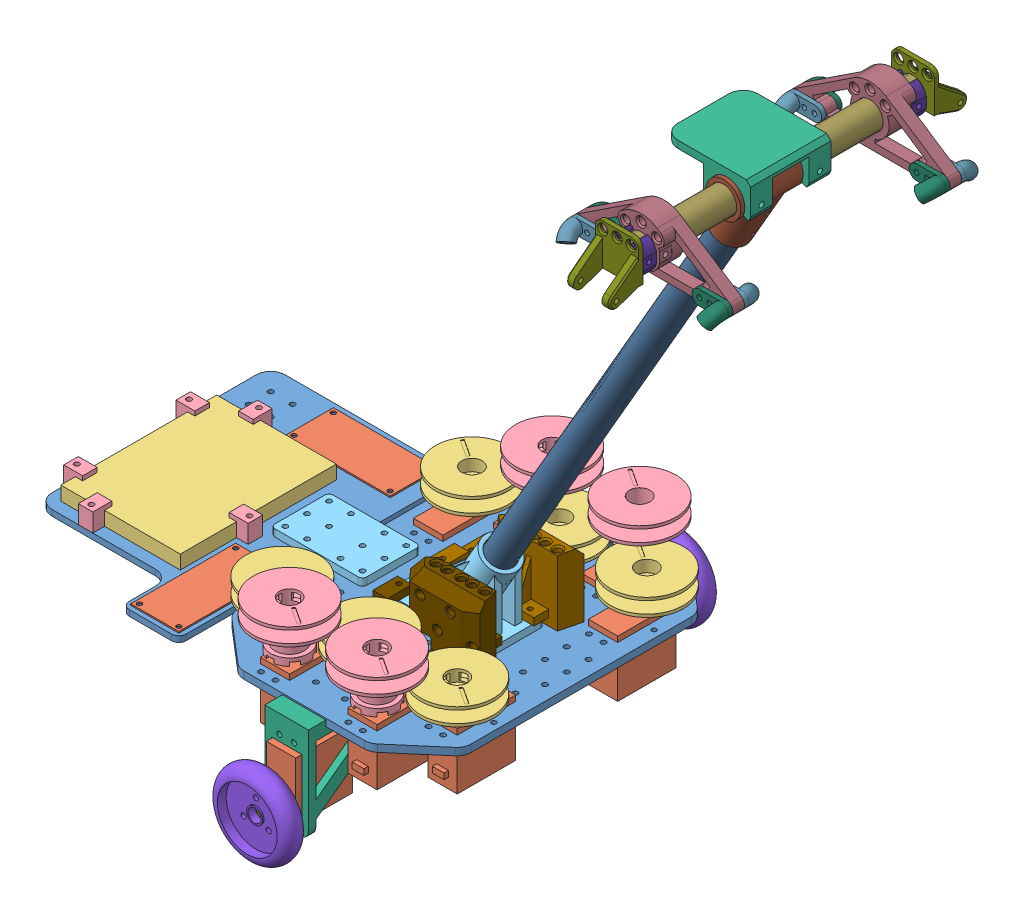
SolidWorks assembly link_root, configuration ﾃﾞﾌｫﾙﾄ. Lengths in mm.
Overall size (475.55 460.7 298.2).
76 component instances, 24 part files, 39 mates.
Components (placement in the parent):
- base_motor-1: base_motor [ﾃﾞﾌｫﾙﾄ] at origin size (192.73 130.6 298.2)
  - base-1: base [ﾃﾞﾌｫﾙﾄ] at origin size (160.1 5 220.2)
  - motor-1: motor [ﾃﾞﾌｫﾙﾄ] at (0 -30 -30.05) x (0 0 1) z (-1 0 0) size (73.36 59.5 70.97)
    - FB5311M-1: FB5311M [ﾃﾞﾌｫﾙﾄ] at origin size (54 44.25 20.1)
    - servo_horn_short-1: servo_horn_short [ﾃﾞﾌｫﾙﾄ] at (-10 42.5 0) x (-0.837169 0 -0.546944) z (0 1 0) size (50 57.04 17)
  - motor-2: motor [ﾃﾞﾌｫﾙﾄ] at (-60 -30 -30.05) x (0 0 1) z (-1 0 0) size (73.36 59.5 70.97)
    - FB5311M-1: FB5311M [ﾃﾞﾌｫﾙﾄ] at origin size (54 44.25 20.1)
    - servo_horn_short-1: servo_horn_short [ﾃﾞﾌｫﾙﾄ] at (-10 42.5 0) x (-0.837169 0 -0.546944) z (0 1 0) size (50 57.04 17)
  - motor-3: motor [ﾃﾞﾌｫﾙﾄ] at (60 -30 -30.05) x (0 0 1) z (-1 0 0) size (73.36 59.5 70.97)
    - FB5311M-1: FB5311M [ﾃﾞﾌｫﾙﾄ] at origin size (54 44.25 20.1)
    - servo_horn_short-1: servo_horn_short [ﾃﾞﾌｫﾙﾄ] at (-10 42.5 0) x (-0.837169 0 -0.546944) z (0 1 0) size (50 57.04 17)
  - motor_long-6: motor_long [ﾃﾞﾌｫﾙﾄ] at (-30 -30 -55.05) x (0 0 1) z (-1 0 0) size (75.45 74.5 73.44) (flexible)
    - FB5311M-1: FB5311M [ﾃﾞﾌｫﾙﾄ] at origin size (54 44.25 20.1)
    - servo_horn_long-1: servo_horn_long [ﾃﾞﾌｫﾙﾄ] at (-10 42.5 0) x (0.789041 0 0.61434) z (0 1 0) size (50 57.04 32)
  - motor_long-5: motor_long [ﾃﾞﾌｫﾙﾄ] at (30 -30 -55.05) x (0 0 1) z (-1 0 0) size (75.45 74.5 73.44)
    - FB5311M-1: FB5311M [ﾃﾞﾌｫﾙﾄ] at origin size (54 44.25 20.1)
    - servo_horn_long-1: servo_horn_long [ﾃﾞﾌｫﾙﾄ] at (-10 42.5 0) x (-0.837169 0 -0.546944) z (0 1 0) size (50 57.04 32)
  - connector_45-1: connector_45 [ﾃﾞﾌｫﾙﾄ] at (0 10 25) x (0 0 1) z (0 1 0) size (40 70.39 54.3)
  - motor-4: motor [ﾃﾞﾌｫﾙﾄ] at (-60 -30 80.05) x (0 0 -1) z (1 0 0) size (73.36 59.5 70.97)
    - FB5311M-1: FB5311M [ﾃﾞﾌｫﾙﾄ] at origin size (54 44.25 20.1)
    - servo_horn_short-1: servo_horn_short [ﾃﾞﾌｫﾙﾄ] at (-10 42.5 0) x (-0.837169 0 -0.546944) z (0 1 0) size (50 57.04 17)
  - motor-5: motor [ﾃﾞﾌｫﾙﾄ] at (0 -30 80.05) x (0 0 -1) z (1 0 0) size (73.36 59.5 70.97)
    - FB5311M-1: FB5311M [ﾃﾞﾌｫﾙﾄ] at origin size (54 44.25 20.1)
    - servo_horn_short-1: servo_horn_short [ﾃﾞﾌｫﾙﾄ] at (-10 42.5 0) x (-0.837169 0 -0.546944) z (0 1 0) size (50 57.04 17)
  - motor-6: motor [ﾃﾞﾌｫﾙﾄ] at (60 -30 80.05) x (0 0 -1) z (1 0 0) size (73.36 59.5 70.97)
    - FB5311M-1: FB5311M [ﾃﾞﾌｫﾙﾄ] at origin size (54 44.25 20.1)
    - servo_horn_short-1: servo_horn_short [ﾃﾞﾌｫﾙﾄ] at (-10 42.5 0) x (-0.837169 0 -0.546944) z (0 1 0) size (50 57.04 17)
  - motor_long-7: motor_long [ﾃﾞﾌｫﾙﾄ] at (-30 -30 105.05) x (0 0 -1) z (1 0 0) size (75.45 74.5 73.44)
    - FB5311M-1: FB5311M [ﾃﾞﾌｫﾙﾄ] at origin size (54 44.25 20.1)
    - servo_horn_long-1: servo_horn_long [ﾃﾞﾌｫﾙﾄ] at (-10 42.5 0) x (-0.837169 0 -0.546944) z (0 1 0) size (50 57.04 32)
  - motor_long-8: motor_long [ﾃﾞﾌｫﾙﾄ] at (30 -30 105.05) x (0 0 -1) z (1 0 0) size (75.45 74.5 73.44)
    - FB5311M-1: FB5311M [ﾃﾞﾌｫﾙﾄ] at origin size (54 44.25 20.1)
    - servo_horn_long-1: servo_horn_long [ﾃﾞﾌｫﾙﾄ] at (-10 42.5 0) x (-0.837169 0 -0.546944) z (0 1 0) size (50 57.04 32)
  - wheel_motor-1: wheel_motor [ﾃﾞﾌｫﾙﾄ] at (15 -61.5 -92.1) x (-1 0 0) z (0 0 -1) size (56 75.3 72)
    - wheel_motor_mount-1: wheel_motor_mount [ﾃﾞﾌｫﾙﾄ] at origin size (30 65.5 45)
    - FB5311M-1: FB5311M [ﾃﾞﾌｫﾙﾄ] at (15 28.2 -30) x (0 1 0) z (1 0 0) size (54 44.25 20.1)
    - wheel_horn-1: wheel_horn [ﾃﾞﾌｫﾙﾄ] at (15 18.2 15.5) size (26 26 10.5)
    - tire-1: tire [ﾃﾞﾌｫﾙﾄ] at (15 18.2 24.5) x (0 0 -1) z (1 0 0) size (15 56 56)
  - wheel_motor-2: wheel_motor [ﾃﾞﾌｫﾙﾄ] at (-15 -61.5 142.1) size (56 75.3 72)
    - wheel_motor_mount-1: wheel_motor_mount [ﾃﾞﾌｫﾙﾄ] at origin size (30 65.5 45)
    - FB5311M-1: FB5311M [ﾃﾞﾌｫﾙﾄ] at (15 28.2 -30) x (0 1 0) z (1 0 0) size (54 44.25 20.1)
    - wheel_horn-1: wheel_horn [ﾃﾞﾌｫﾙﾄ] at (15 18.2 15.5) size (26 26 10.5)
    - tire-1: tire [ﾃﾞﾌｫﾙﾄ] at (15 18.2 24.5) x (0 0 -1) z (1 0 0) size (15 56 56)
- root_connector_loft-1: root_connector_loft [ﾃﾞﾌｫﾙﾄ] at (0 5 -10) x (0 0 -1) z (1 0 0) size (39 45 81.16)
- pipe_body-1: pipe_body [body] at (202.5 360.7403 25) x (-0.866025 0.5 0) z (-0.5 -0.866025 0) size (18 18 400)
- connector_T-1: connector_T [ﾃﾞﾌｫﾙﾄ] at (207.5 369.4005 25) x (-0.5 -0.866025 0) z (-0.866025 0.5 0) size (62 60 24)
- pipe_shoulder-1: pipe_shoulder [ﾃﾞﾌｫﾙﾄ] at (207.5 369.4005 -75) size (18 18 200)
- assem_shoulder-3: assem_shoulder [left] at (207.5 369.4005 -45.5) x (-1 0 0) z (0 0 -1) size (110 42.64 39.98)
  - wire_root_curve-1: wire_root_curve [ﾃﾞﾌｫﾙﾄ] at origin size (110 40 16)
  - wire_root_curve_support-1: wire_root_curve_support [ﾃﾞﾌｫﾙﾄ] at (-50 -15 11) size (25 12.64 15.99)
  - wire_root_curve_support_mirror-1: wire_root_curve_support_mirror [ﾃﾞﾌｫﾙﾄ] at (50 -15 5) x (-1 0 0) z (0 0 -1) size (25 12.64 15.99)
  - wire_root_curve_support-2: wire_root_curve_support [45] at (50 -15 -3) x (-1 0 0) z (0 0 -1) size (25 12.5 15.99)
  - wire_root_curve_support_mirror-2: wire_root_curve_support_mirror [76] at (-50 -15 3) size (25 12.37 15.99)
- assem_shoulder-2: assem_shoulder [ﾃﾞﾌｫﾙﾄ] at (207.5 369.4005 95.5) size (110 42.64 39.98)
  - wire_root_curve-1: wire_root_curve [ﾃﾞﾌｫﾙﾄ] at origin size (110 40 16)
  - wire_root_curve_support-1: wire_root_curve_support [ﾃﾞﾌｫﾙﾄ] at (-50 -15 11) size (25 12.64 15.99)
  - wire_root_curve_support_mirror-1: wire_root_curve_support_mirror [ﾃﾞﾌｫﾙﾄ] at (50 -15 5) x (-1 0 0) z (0 0 -1) size (25 12.64 15.99)
  - wire_root_curve_support-2: wire_root_curve_support [76] at (50 -15 -3) x (-1 0 0) z (0 0 -1) size (25 12.37 15.99)
  - wire_root_curve_support_mirror-2: wire_root_curve_support_mirror [45] at (-50 -15 3) size (25 12.5 15.99)
- shoulder3-1: shoulder3 [ﾃﾞﾌｫﾙﾄ] at (207.5 369.4005 -60) x (1 0 0) z (0 0 -1) size (29.5 33 38)
- shoulder3-2: shoulder3 [ﾃﾞﾌｫﾙﾄ] at (207.5 369.4005 110) x (-1 0 0) z (0 0 1) size (29.5 33 38)
- shoulder_patch-1: shoulder_patch [ﾃﾞﾌｫﾙﾄ] at (207.5 369.4005 112.5) size (23.48 22.98 10)
- shoulder_patch-2: shoulder_patch [ﾃﾞﾌｫﾙﾄ] at (207.5 369.4005 -72.5) size (23.48 22.98 10)
- root_connector_loft_mirror-1: root_connector_loft_mirror [ﾃﾞﾌｫﾙﾄ] at (0 5 60) x (0 0 -1) z (1 0 0) size (39 45 81.16)
- circuit-1: circuit [ﾃﾞﾌｫﾙﾄ] at (-148.05 1 25) x (0 0 1) z (-1 0 0) size (193 16.5 130)
  - circuit_board-1: circuit_board [ﾃﾞﾌｫﾙﾄ] at origin size (193 4 130)
  - PCA9685-1: PCA9685 [ﾃﾞﾌｫﾙﾄ] at (-59.5 4 -18) x (0 0 1) z (-1 0 0) size (72 1 33)
  - breadboard-1: breadboard [ﾃﾞﾌｫﾙﾄ] at (18.5 4 16) size (107 9.5 82)
  - PCA9685-2: PCA9685 [ﾃﾞﾌｫﾙﾄ] at (74 4 -45.5) x (-1 0 0) z (0 0 -1) size (72 1 33)
  - breadboard_support-1: breadboard_support [ﾃﾞﾌｫﾙﾄ] at (72 4 27) size (13 12.5 10)
  - breadboard_support-2: breadboard_support [ﾃﾞﾌｫﾙﾄ] at (62 4 57) x (0 0 1) z (-1 0 0) size (13 12.5 10)
  - breadboard_support-3: breadboard_support [ﾃﾞﾌｫﾙﾄ] at (-15 4 57) x (0 0 1) z (-1 0 0) size (13 12.5 10)
  - breadboard_support-4: breadboard_support [ﾃﾞﾌｫﾙﾄ] at (-35 4 37) x (-1 0 0) z (0 0 -1) size (13 12.5 10)
  - breadboard_support-5: breadboard_support [ﾃﾞﾌｫﾙﾄ] at (23.5 4 -25) x (0 0 -1) z (1 0 0) size (13 12.5 10)
- board_connect-1: board_connect [ﾃﾞﾌｫﾙﾄ] at (-81.55 5 25) x (0 0 -1) z (1 0 0) size (40 5 63)
- camera_mount-1: camera_mount [ﾃﾞﾌｫﾙﾄ] at (207.5 369.4005 25) x (0 0 1) z (-1 0 0) size (55 23.79 60)
Mates (geometry in assembly coordinates):
- 同心円2: concentric anti-aligned: cylinder of base_motor-1/base-1 through (-20 0 -20) axis (0 1 0) radius 1.75; cylinder of root_connector_loft-1 through (-20 10 -20) axis (0 -1 0) radius 1.75
- 同心円3: concentric anti-aligned: cylinder of base_motor-1/base-1 through (-30 0 -10) axis (0 1 0) radius 1.75; cylinder of root_connector_loft-1 through (-30 10 -10) axis (0 -1 0) radius 1.75
- 一致1: coincident anti-aligned: plane of base_motor-1/base-1 through (0 5 50) normal (0 1 0); plane of root_connector_loft-1 through (0 5 -10) normal (0 -1 0)
- 同心円6: concentric aligned: cylinder of base_motor-1/connector_45-1 through (-10.9151 -8.9054 25) axis (0.5 0.866025 0) radius 9.4; cylinder of pipe_body-1 through (2.5 14.3301 25) axis (0.5 0.866025 0) radius 9
- 同心円7: concentric anti-aligned: cylinder of base_motor-1/connector_45-1 through (-27.5993 72.1225 25) axis (0.866025 -0.5 0) radius 1.75; cylinder of pipe_body-1 through (27.7942 40.141 25) axis (-0.866025 0.5 0) radius 1.75
- 同心円8: concentric anti-aligned: cylinder of pipe_body-1 through (2.5 14.3301 25) axis (0.5 0.866025 0) radius 9; cylinder of connector_T-1 through (213.501 379.7946 25) axis (-0.5 -0.866025 0) radius 9.25
- 同心円9: concentric aligned: cylinder of pipe_body-1 through (205.2942 347.58 25) axis (-0.866025 0.5 0) radius 1.75; cylinder of connector_T-1 through (207.8923 346.08 25) axis (-0.866025 0.5 0) radius 1.75
- 同心円10: concentric aligned: cylinder of connector_T-1 through (207.5 369.4005 55) axis (0 0 -1) radius 9.25; cylinder of pipe_shoulder-1 through (207.5 369.4005 125) axis (0 0 -1) radius 9
- 同心円11: concentric anti-aligned: cylinder of connector_T-1 through (223.8923 369.4005 45) axis (-1 0 0) radius 1.75; cylinder of pipe_shoulder-1 through (198.5 369.4005 45) axis (1 0 0) radius 1.75
- 同心円12: concentric anti-aligned: cylinder of pipe_shoulder-1 through (207.5 369.4005 125) axis (0 0 -1) radius 9; cylinder of assem_shoulder-3/wire_root_curve-1 through (207.5 369.4005 -53.5) axis (0 0 1) radius 9.25
- 同心円13: concentric anti-aligned: cylinder of pipe_shoulder-1 through (198.5 369.4005 -57.5) axis (1 0 0) radius 1.75; cylinder of assem_shoulder-3/wire_root_curve-1 through (262.5 369.4005 -57.5) axis (-1 0 0) radius 1.75
- 同心円14: concentric aligned: cylinder of pipe_shoulder-1 through (207.5 369.4005 125) axis (0 0 -1) radius 9; cylinder of assem_shoulder_r-2/wire_root_curve-1 through (207.5 369.4005 103.5) axis (0 0 -1) radius 9.25
- 同心円15: concentric aligned: cylinder of pipe_shoulder-1 through (198.5 369.4005 107.5) axis (1 0 0) radius 1.75; cylinder of assem_shoulder_r-2/wire_root_curve-1 through (152.5 369.4005 107.5) axis (1 0 0) radius 1.75
- 同心円16: concentric anti-aligned: cylinder of pipe_shoulder-1 through (207.5 369.4005 125) axis (0 0 -1) radius 6.25; cylinder of shoulder3-1 through (207.5 369.4005 -75) axis (0 0 1) radius 6.45
- 同心円17: concentric aligned: cylinder of pipe_shoulder-1 through (198.5 369.4005 -67.5) axis (1 0 0) radius 1.75; cylinder of shoulder3-1 through (192.75 369.4005 -67.5) axis (1 0 0) radius 1.65
- 同心円18: concentric aligned: cylinder of pipe_shoulder-1 through (207.5 369.4005 125) axis (0 0 -1) radius 6.25; cylinder of shoulder3-2 through (207.5 369.4005 125) axis (0 0 -1) radius 6.45
- 同心円19: concentric anti-aligned: cylinder of pipe_shoulder-1 through (198.5 369.4005 117.5) axis (1 0 0) radius 1.75; cylinder of shoulder3-2 through (222.25 369.4005 117.5) axis (-1 0 0) radius 1.65
- 同心円20: concentric aligned: cylinder of pipe_shoulder-1 through (207.5 369.4005 125) axis (0 0 -1) radius 9; cylinder of shoulder_patch-1 through (207.5 369.4005 122.5) axis (0 0 -1) radius 9.25
- 同心円21: concentric aligned: cylinder of pipe_shoulder-1 through (198.5 369.4005 117.5) axis (1 0 0) radius 1.75; cylinder of shoulder_patch-1 through (195.7606 369.4005 117.5) axis (1 0 0) radius 1.65
- 同心円22: concentric aligned: cylinder of pipe_shoulder-1 through (207.5 369.4005 125) axis (0 0 -1) radius 9; cylinder of shoulder_patch-2 through (207.5 369.4005 -62.5) axis (0 0 -1) radius 9.25
- 同心円23: concentric aligned: cylinder of pipe_shoulder-1 through (198.5 369.4005 -67.5) axis (1 0 0) radius 1.75; cylinder of shoulder_patch-2 through (195.7606 369.4005 -67.5) axis (1 0 0) radius 1.65
- 同心円24: concentric aligned: cylinder of base_motor-1/wheel_support-1 through (0 -50 -60.85) axis (0 0 1) radius 2; cylinder of wheel-1 through (0 -50 -71.1) axis (0 0 1) radius 2.45
- 幅1: width anti-aligned: plane of base_motor-1/wheel_support-1 through (0 -50 -73.35) normal (0 0 1); plane of wheel-1 through (0 -50 -60.85) normal (0 0 -1); plane of base_motor-1/wheel_support-1 through (0 -50 -71.1) normal (0 0 -1); plane of wheel-1 through (0 -50 -63.1) normal (0 0 1)
- 同心円25: concentric aligned: cylinder of base_motor-1/wheel_support-2 through (0 -50 123.35) axis (0 0 1) radius 2; cylinder of wheel-2 through (0 -50 113.1) axis (0 0 1) radius 2.45
- 幅2: width anti-aligned: plane of base_motor-1/wheel_support-2 through (0 -50 123.35) normal (0 0 -1); plane of wheel-2 through (0 -50 110.85) normal (0 0 1); plane of base_motor-1/wheel_support-2 through (0 -50 121.1) normal (0 0 1); plane of wheel-2 through (0 -50 113.1) normal (0 0 -1)
- 同心円26: concentric anti-aligned: cylinder of base_motor-1/connector_45-1 through (-30 59.3023 40) axis (0 -1 0) radius 1.75; cylinder of root_connector_loft_mirror-1 through (-30 4.999 40) axis (0 1 0) radius 1.65
- 同心円27: concentric anti-aligned: cylinder of base_motor-1/base-1 through (-30 0 60) axis (0 1 0) radius 1.75; cylinder of root_connector_loft_mirror-1 through (-30 10 60) axis (0 -1 0) radius 1.75
- 同心円28: concentric anti-aligned: cylinder of base_motor-1/base-1 through (-20 0 70) axis (0 1 0) radius 1.75; cylinder of root_connector_loft_mirror-1 through (-20 10 70) axis (0 -1 0) radius 1.75
- 同心円29: concentric anti-aligned: cylinder of base_motor-1/connector_45-1 through (30 59.3023 40) axis (0 -1 0) radius 1.75; cylinder of root_connector_loft_mirror-1 through (30 4.999 40) axis (0 1 0) radius 1.65
- 一致2: coincident anti-aligned: plane of base_motor-1/base-1 through (0 5 50) normal (0 1 0); plane of root_connector_loft_mirror-1 through (0 5 60) normal (0 -1 0)
- 同心円30: concentric anti-aligned: cylinder of base_motor-1/base-1 through (-55.05 0 40) axis (0 1 0) radius 1.75; cylinder of board_connect-1 through (-55.05 10 40) axis (0 -1 0) radius 1.7
- 同心円31: concentric anti-aligned: cylinder of base_motor-1/base-1 through (-70.05 0 40) axis (0 1 0) radius 1.75; cylinder of board_connect-1 through (-70.05 10 40) axis (0 -1 0) radius 1.7
- 一致3: coincident anti-aligned: plane of base_motor-1/base-1 through (0 5 50) normal (0 1 0); plane of board_connect-1 through (-81.55 5 25) normal (0 -1 0)
- 同心円32: concentric anti-aligned: cylinder of circuit-1/circuit_board-1 through (-93.05 1 10) axis (0 1 0) radius 1.75; cylinder of board_connect-1 through (-93.05 10 10) axis (0 -1 0) radius 1.7
- 同心円33: concentric anti-aligned: cylinder of circuit-1/circuit_board-1 through (-108.05 1 25) axis (0 1 0) radius 1.75; cylinder of board_connect-1 through (-108.05 10 25) axis (0 -1 0) radius 1.7
- 一致4: coincident anti-aligned: plane of circuit-1/circuit_board-1 through (-148.05 5 25) normal (0 1 0); plane of board_connect-1 through (-81.55 5 25) normal (0 -1 0)
- 同心円34: concentric anti-aligned: cylinder of connector_T-1 through (223.8923 369.4005 45) axis (-1 0 0) radius 1.75; cylinder of camera_mount-1 through (163.75 369.4005 45) axis (1 0 0) radius 1.75
- 同心円35: concentric anti-aligned: cylinder of connector_T-1 through (223.8923 369.4005 5) axis (-1 0 0) radius 1.75; cylinder of camera_mount-1 through (163.75 369.4005 5) axis (1 0 0) radius 1.75
- 同心円36: concentric aligned: cylinder of connector_T-1 through (207.5 369.4005 55) axis (0 0 -1) radius 12; cylinder of camera_mount-1 through (207.5 369.4005 52.5) axis (0 0 -1) radius 12.25
